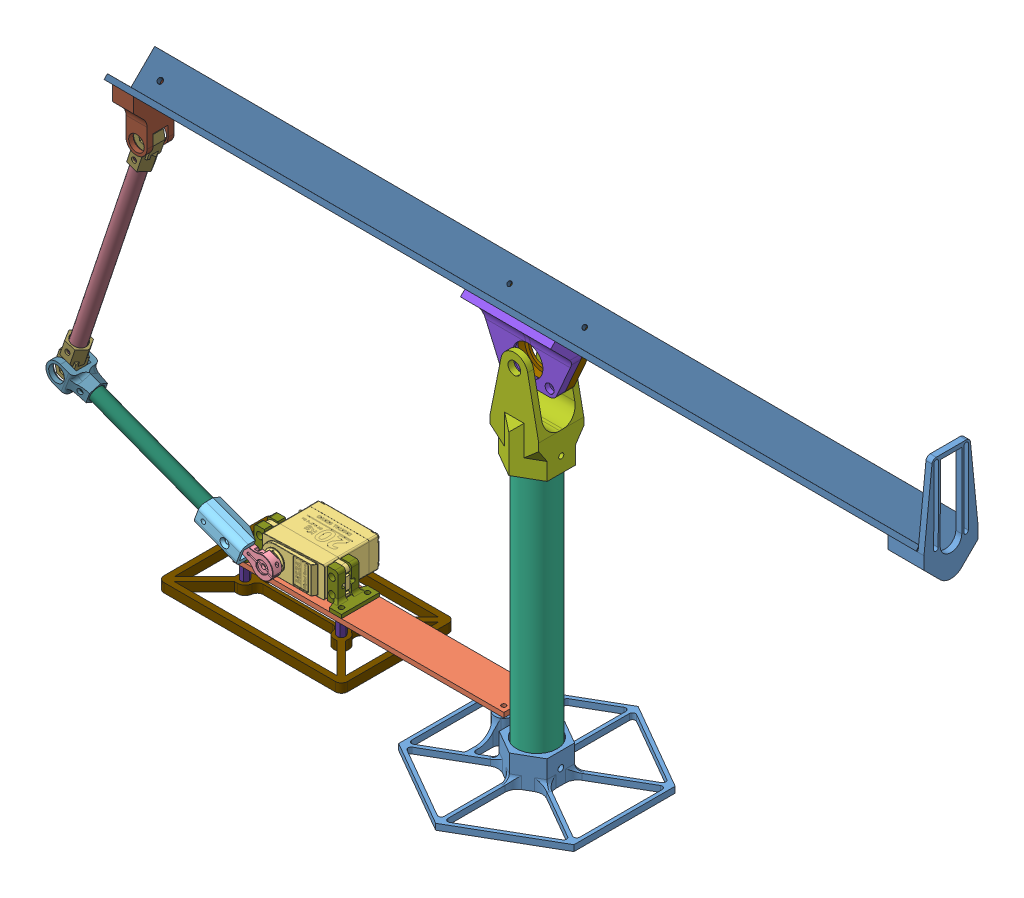
SolidWorks assembly Ensamblaje2, configuration Predeterminado. Lengths in mm.
Overall size (595.06 324.02 134.64).
24 component instances, 19 part files, 50 mates.
Components (placement in the parent):
- Soporte_base-1: Soporte_base [Predeterminado] at (0.7319 45.2828 116.0405) x (0 0 1) z (1 0 0) size (134.64 20.58 116.6)
- platina-1: platina [Predeterminado] at (-115.2681 61.2828 99.3405) size (180 3.17 25.4)
- DS3218MG MS24 Digital Servo 270-1: DS3218MG MS24 Digital Servo 270 [Default] at (-179.2681 74.4678 97.7405) x (0 1 0) z (1 0 0) size (20.1 45.99 55.6)
- Servo Arm for DS3218MG-1: Servo Arm for DS3218MG [Default] at (-179.2681 74.4678 118.9405) x (-0.353521 -0.935426 0) z (-0.935426 0.353521 0) size (14.5 6.15 35.53)
- brazo_servo_acople-1: brazo_servo_acople [Predeterminado] at (-207.7986 85.2502 116.0405) x (-0.353521 -0.935426 0) z (0 0 1) size (14.32 30 14.8)
- Tubo_soporte-1: Tubo_soporte [Predeterminado] at (0.7319 45.2828 116.0405) x (0 0 1) z (-1 0 0) size (25.4 200 25.4)
- Articulacion_eje-1: Articulacion_eje [Predeterminado] at (0.7319 250.2828 116.0405) x (0 0 1) z (-1 0 0) size (37.41 69 32.4)
- Soporte_barra_frontal-1: Soporte_barra_frontal [Predeterminado] at (0.7733 299.2827 116.0405) x (0.999996 -0.002954 0) z (-0.002954 -0.999996 0) size (60 20.96 45.96)
- Soporte_barra_posterior-1: Soporte_barra_posterior [Predeterminado] at (0.7733 299.2827 116.0405) x (-0.999996 0.002954 0) z (-0.002954 -0.999996 0) size (60 20.96 45.96)
- Barra-1: Barra [Predeterminado] at (0.7733 299.2827 116.0405) x (0.999996 -0.002954 0) z (0.002089 0.707104 0.707107) size (540 25.4 25.4)
- acople_rodamiento_barra-1: acople_rodamiento_barra [Predeterminado] at (-256.5755 283.1433 116.0405) x (0 0 -1) z (0.999996 -0.002954 0) size (35.92 41.86 14)
- acople_brazo-1: acople_brazo [Predeterminado] at (-256.5755 283.1433 116.0405) x (0 0 1) z (0.948568 -0.316575 0) size (12.4 24 14.32)
- brazo2-1: brazo2 [Predeterminado] at (-306.9109 132.3211 116.0405) x (0 0 -1) z (0.948568 -0.316575 0) size (9 150 9)
- acople_brazos-1: acople_brazos [Predeterminado] at (-309.7601 123.784 116.0405) x (0 0 -1) z (-0.353521 -0.935426 0) size (18 26 14)
- acople_brazo-2: acople_brazo [Predeterminado] at (-309.7601 123.784 116.0405) x (0 0 -1) z (0.948568 -0.316575 0) size (12.4 24 14.32)
- brazo-100mm-1: brazo-100mm [Predeterminado] at (-301.3413 120.6023 116.0405) x (0 0 1) z (0.353521 0.935426 0) size (9 100 9)
- Soporte_servo-1: Soporte_servo [Predeterminado] at (-143.2681 64.4678 99.3405) size (15 20 25.4)
- Soporte_servo-2: Soporte_servo [Predeterminado] at (-195.2681 64.4678 99.3405) x (-1 0 0) z (0 0 -1) size (15 20 25.4)
- M3_F_TO_F_10MM_STANDOFF.step-1: M3_F_TO_F_10MM_STANDOFF.step [Predeterminado] at (-137.2681 56.2828 108.0405) x (1 0 0) z (0 -1 0) size (5.78 5.78 10)
- M3_F_TO_F_10MM_STANDOFF.step-2: M3_F_TO_F_10MM_STANDOFF.step [Predeterminado] at (-201.2681 56.2828 90.6405) x (1 0 0) z (0 -1 0) size (5.78 5.78 10)
- M3_F_TO_F_10MM_STANDOFF.step-3: M3_F_TO_F_10MM_STANDOFF.step [Predeterminado] at (-137.2681 56.2828 90.6405) x (1 0 0) z (0 -1 0) size (5.78 5.78 10)
- M3_F_TO_F_10MM_STANDOFF.step-4: M3_F_TO_F_10MM_STANDOFF.step [Predeterminado] at (-201.2681 56.2828 108.0405) x (1 0 0) z (0 -1 0) size (5.78 5.78 10)
- base_servo-1: base_servo [Predeterminado] at (-169.2681 45.2828 99.3405) size (122 6 75.4)
- Soporte_sensor-1: Soporte_sensor [Predeterminado] at (272.0721 298.4813 116.0405) x (0 0 -1) z (0.999996 -0.002954 0) size (35.92 75.1 24)
Mates (geometry in assembly coordinates):
- Concéntrica1: concentric aligned: cylinder of Soporte_base-1 through (-29.2681 61.2828 90.6405) axis (0 -1 0) radius 1.8; cylinder of platina-1 through (-29.2681 64.4578 90.6405) axis (0 -1 0) radius 1.5
- Concéntrica2: concentric aligned: cylinder of Soporte_base-1 through (-29.2681 61.2828 108.0405) axis (0 -1 0) radius 1.8; cylinder of platina-1 through (-29.2681 64.4578 108.0405) axis (0 -1 0) radius 1.5
- Coincidente1: coincident anti-aligned: plane of Soporte_base-1 through (0.7319 61.2828 116.0405) normal (0 1 0); plane of platina-1 through (-115.2681 61.2828 99.3405) normal (0 -1 0)
- Concéntrica12: concentric aligned: cylinder of DS3218MG MS24 Digital Servo 270-1 through (-179.2681 74.4678 112.1405) axis (0 0 1) radius 1.25; cylinder of Servo Arm for DS3218MG-1 through (-179.2681 74.4678 112.9405) axis (0 0 1) radius 1.5
- Concéntrica13: concentric aligned: circle of Servo Arm for DS3218MG-1; cylinder of brazo_servo_acople-1 through (-202.186 83.129 97.629) axis (0 0 1) radius 1.5
- Concéntrica14: concentric anti-aligned: circle of Servo Arm for DS3218MG-1; cylinder of brazo_servo_acople-1 through (-198.4443 81.715 124.6405) axis (0 0 -1) radius 1.5
- Concéntrica15: concentric anti-aligned: cylinder of Soporte_base-1 through (-20.5421 55.2828 116.0405) axis (1 0 0) radius 1.9; cylinder of Tubo_soporte-1 through (13.4319 55.2828 116.0405) axis (-1 0 0) radius 1.5
- Concéntrica16: concentric aligned: cylinder of Soporte_base-1 through (0.7319 65.2828 116.0405) axis (0 -1 0) radius 13.5; cylinder of Tubo_soporte-1 through (0.7319 245.2828 116.0405) axis (0 -1 0) radius 12.7
- Concéntrica17: concentric aligned: cylinder of Tubo_soporte-1 through (13.4319 235.2828 116.0405) axis (-1 0 0) radius 1.5; cylinder of Articulacion_eje-1 through (21.7402 235.2828 116.0405) axis (-1 0 0) radius 1.7
- Concéntrica18: concentric anti-aligned: cylinder of Tubo_soporte-1 through (0.7319 245.2828 116.0405) axis (0 -1 0) radius 12.7; cylinder of Articulacion_eje-1 through (0.7319 225.2828 116.0405) axis (0 1 0) radius 13.1
- Coincidente5: coincident anti-aligned: plane of Soporte_barra_frontal-1 through (-29.2266 299.3713 116.0405) normal (0 0 -1); plane of Soporte_barra_posterior-1 through (30.7731 299.1941 116.0405) normal (0 0 1)
- Concéntrica19: concentric anti-aligned: cylinder of Soporte_barra_frontal-1 through (0.7319 285.2828 154.0444) axis (0 0 -1) radius 10; cylinder of Soporte_barra_posterior-1 through (0.7319 285.2828 78.0366) axis (0 0 1) radius 10
- Concéntrica20: concentric anti-aligned: cylinder of Soporte_barra_posterior-1 through (25.7805 301.6891 100.5602) axis (0.002089 0.707104 0.707107) radius 1.75; cylinder of Barra-1 through (25.8166 313.9341 112.8053) axis (-0.002089 -0.707104 -0.707107) radius 1.5
- Concéntrica21: concentric aligned: cylinder of Soporte_barra_frontal-1 through (-24.2048 306.751 126.6065) axis (-0.002089 -0.707104 0.707107) radius 3; cylinder of Barra-1 through (-24.1831 314.0818 119.2757) axis (-0.002089 -0.707104 0.707107) radius 1.5
- Ancho2: width anti-aligned: plane of Soporte_barra_frontal-1 through (-29.3093 271.3715 122.0405) normal (0 0 1); plane of Soporte_barra_posterior-1 through (30.6904 271.1942 110.0405) normal (0 0 -1); plane of Articulacion_eje-1 through (0.7319 250.2828 127.0405) normal (0 0 -1); plane of Articulacion_eje-1 through (0.7319 250.2828 105.0405) normal (0 0 1)
- Concéntrica22: concentric aligned: cylinder of Articulacion_eje-1 through (0.7319 285.2828 101.0405) axis (0 0 1) radius 4.2; cylinder of Soporte_barra_posterior-1 through (0.7319 285.2828 111.6405) axis (0 0 1) radius 12.5
- Ancho3: width anti-aligned: plane of acople_rodamiento_barra-1 through (-256.5755 283.1433 111.0405) normal (0 0 1); plane of acople_rodamiento_barra-1 through (-256.5755 283.1433 121.0405) normal (0 0 -1); plane of acople_brazo-1 through (-256.5755 283.1433 111.4405) normal (0 0 -1); plane of acople_brazo-1 through (-256.5755 283.1433 120.6405) normal (0 0 1)
- Concéntrica23: concentric aligned: cylinder of acople_rodamiento_barra-1 through (-256.5755 283.1433 122.0405) axis (0 0 1) radius 5.2; circle of acople_brazo-1
- Concéntrica24: concentric anti-aligned: cylinder of Barra-1 through (-256.4821 314.768 119.2757) axis (-0.002089 -0.707104 0.707107) radius 1.75; cylinder of acople_rodamiento_barra-1 through (-256.5238 300.6733 133.3705) axis (0.002089 0.707104 -0.707107) radius 1.7
- Concéntrica25: concentric anti-aligned: cylinder of Barra-1 through (-256.4821 314.768 112.8053) axis (-0.002089 -0.707104 -0.707107) radius 1.75; cylinder of acople_rodamiento_barra-1 through (-256.5238 300.6733 98.7105) axis (0.002089 0.707104 0.707107) radius 1.7
- Concéntrica26: concentric anti-aligned: cylinder of acople_brazo-1 through (-261.0076 269.8634 109.8405) axis (0 0 1) radius 1.7; cylinder of brazo2-1 through (-261.0076 269.8634 120.5405) axis (0 0 -1) radius 1.5
- Concéntrica27: concentric anti-aligned: cylinder of acople_brazo-1 through (-262.5905 265.1206 116.0405) axis (0.316575 0.948568 0) radius 5; cylinder of brazo2-1 through (-259.4247 274.6062 116.0405) axis (-0.316575 -0.948568 0) radius 4.5
- Concéntrica28: concentric aligned: cylinder of brazo2-1 through (-305.328 137.0639 120.5405) axis (0 0 -1) radius 1.5; cylinder of acople_brazo-2 through (-305.328 137.0639 122.2405) axis (0 0 -1) radius 1.7
- Concéntrica29: concentric aligned: cylinder of brazo2-1 through (-259.4247 274.6062 116.0405) axis (-0.316575 -0.948568 0) radius 4.5; cylinder of acople_brazo-2 through (-303.7452 141.8068 116.0405) axis (-0.316575 -0.948568 0) radius 5
- Ancho4: width anti-aligned: plane of acople_brazos-1 through (-309.7601 123.784 111.0405) normal (0 0 1); plane of acople_brazos-1 through (-309.7601 123.784 121.0405) normal (0 0 -1); plane of acople_brazo-2 through (-309.7601 123.784 111.4405) normal (0 0 -1); plane of acople_brazo-2 through (-309.7601 123.784 120.6405) normal (0 0 1)
- Concéntrica30: concentric anti-aligned: cylinder of acople_brazos-1 through (-309.7601 123.784 122.0405) axis (0 0 1) radius 5.2; circle of acople_brazo-2
- Concéntrica31: concentric anti-aligned: cylinder of acople_brazos-1 through (-296.6641 118.8347 125.0405) axis (0 0 -1) radius 1.7; cylinder of brazo-100mm-1 through (-296.6641 118.8347 111.5405) axis (0 0 1) radius 1.5
- Concéntrica32: concentric aligned: cylinder of acople_brazos-1 through (-291.987 117.0671 116.0405) axis (-0.935426 0.353521 0) radius 5; cylinder of brazo-100mm-1 through (-207.7986 85.2502 116.0405) axis (-0.935426 0.353521 0) radius 4.5
- Concéntrica33: concentric anti-aligned: cylinder of brazo_servo_acople-1 through (-212.4757 87.0178 124.6405) axis (0 0 -1) radius 1.5; cylinder of brazo-100mm-1 through (-212.4757 87.0178 111.5405) axis (0 0 1) radius 1.5
- Concéntrica34: concentric anti-aligned: cylinder of brazo_servo_acople-1 through (-217.1529 88.7854 116.0405) axis (0.935426 -0.353521 0) radius 5; cylinder of brazo-100mm-1 through (-207.7986 85.2502 116.0405) axis (-0.935426 0.353521 0) radius 4.5
- Coincidente7: coincident anti-aligned: plane of Servo Arm for DS3218MG-1 through (-179.2681 74.4678 114.9405) normal (0 0 -1); plane of brazo_servo_acople-1 through (-207.7986 85.2502 114.9405) normal (0 0 1)
- Concéntrica38: concentric anti-aligned: cylinder of DS3218MG MS24 Digital Servo 270-1 through (-193.2681 79.4678 91.3765) axis (0 0 1) radius 2.25; cylinder of Soporte_servo-2 through (-193.2681 79.4678 112.563) axis (0 0 -1) radius 2.2
- Concéntrica39: concentric aligned: cylinder of DS3218MG MS24 Digital Servo 270-1 through (-145.2681 69.4678 91.3765) axis (0 0 1) radius 2.25; cylinder of Soporte_servo-1 through (-145.2681 69.4678 86.1179) axis (0 0 1) radius 2.2
- Concéntrica40: concentric aligned: cylinder of platina-1 through (-201.2681 64.4578 108.0405) axis (0 -1 0) radius 1.5; cylinder of Soporte_servo-2 through (-201.2681 75.895 108.0405) axis (0 -1 0) radius 1.6
- Concéntrica41: concentric aligned: cylinder of platina-1 through (-137.2681 64.4578 90.6405) axis (0 -1 0) radius 1.5; cylinder of Soporte_servo-1 through (-137.2681 75.895 90.6405) axis (0 -1 0) radius 1.6
- Coincidente8: coincident anti-aligned: plane of platina-1 through (-115.2681 64.4578 99.3405) normal (0 1 0); plane of DS3218MG MS24 Digital Servo 270-1 through (-169.099 64.4578 93.2687) normal (0 -1 0)
- Ancho5: width anti-aligned: plane of DS3218MG MS24 Digital Servo 270-1 through (-152.2681 83.4678 97.7405) normal (0 0 -1); plane of DS3218MG MS24 Digital Servo 270-1 through (-179.2681 74.4678 100.9405) normal (0 0 1); plane of Soporte_servo-2 through (-190.2681 64.4678 97.3405) normal (0 0 1); plane of Soporte_servo-2 through (-190.2681 64.4678 101.3405) normal (0 0 -1)
- Coincidente9: coincident aligned: plane of M3_F_TO_F_10MM_STANDOFF.step-2 through (-201.2681 61.2828 90.6405) normal (0 1 0); plane of M3_F_TO_F_10MM_STANDOFF.step-4 through (-201.2681 61.2828 108.0405) normal (0 1 0)
- Coincidente10: coincident aligned: plane of M3_F_TO_F_10MM_STANDOFF.step-2 through (-201.2681 61.2828 90.6405) normal (0 1 0); plane of M3_F_TO_F_10MM_STANDOFF.step-3 through (-137.2681 61.2828 90.6405) normal (0 1 0)
- Coincidente11: coincident aligned: plane of M3_F_TO_F_10MM_STANDOFF.step-1 through (-137.2681 61.2828 108.0405) normal (0 1 0); plane of M3_F_TO_F_10MM_STANDOFF.step-2 through (-201.2681 61.2828 90.6405) normal (0 1 0)
- Coincidente12: coincident anti-aligned: plane of platina-1 through (-115.2681 61.2828 99.3405) normal (0 -1 0); plane of M3_F_TO_F_10MM_STANDOFF.step-2 through (-201.2681 61.2828 90.6405) normal (0 1 0)
- Concéntrica42: concentric aligned: cylinder of platina-1 through (-201.2681 64.4578 90.6405) axis (0 -1 0) radius 1.5; cylinder of M3_F_TO_F_10MM_STANDOFF.step-2 through (-201.2681 51.2828 90.6405) axis (0 -1 0) radius 1.25
- Concéntrica43: concentric aligned: cylinder of platina-1 through (-137.2681 64.4578 90.6405) axis (0 -1 0) radius 1.5; cylinder of M3_F_TO_F_10MM_STANDOFF.step-3 through (-137.2681 51.2828 90.6405) axis (0 -1 0) radius 1.25
- Concéntrica44: concentric aligned: cylinder of platina-1 through (-137.2681 64.4578 108.0405) axis (0 -1 0) radius 1.5; cylinder of M3_F_TO_F_10MM_STANDOFF.step-1 through (-137.2681 51.2828 108.0405) axis (0 -1 0) radius 1.25
- Concéntrica45: concentric aligned: cylinder of platina-1 through (-201.2681 64.4578 108.0405) axis (0 -1 0) radius 1.5; cylinder of M3_F_TO_F_10MM_STANDOFF.step-4 through (-201.2681 51.2828 108.0405) axis (0 -1 0) radius 1.25
- Concéntrica46: concentric aligned: cylinder of M3_F_TO_F_10MM_STANDOFF.step-2 through (-201.2681 51.2828 90.6405) axis (0 -1 0) radius 1.25; cylinder of base_servo-1 through (-201.2681 51.2828 90.6405) axis (0 -1 0) radius 1.6
- Concéntrica47: concentric aligned: cylinder of M3_F_TO_F_10MM_STANDOFF.step-1 through (-137.2681 51.2828 108.0405) axis (0 -1 0) radius 1.25; cylinder of base_servo-1 through (-137.2681 51.2828 108.0405) axis (0 -1 0) radius 1.6
- Coincidente13: coincident anti-aligned: plane of M3_F_TO_F_10MM_STANDOFF.step-4 through (-201.2681 51.2828 108.0405) normal (0 -1 0); plane of base_servo-1 through (-169.2681 51.2828 99.3405) normal (0 1 0)
- Concéntrica48: concentric anti-aligned: cylinder of Barra-1 through (258.1156 313.2479 112.8053) axis (-0.002089 -0.707104 -0.707107) radius 1.75; cylinder of Soporte_sensor-1 through (258.0755 299.6603 99.2176) axis (0.002089 0.707104 0.707107) radius 1.8
- Concéntrica49: concentric aligned: cylinder of Barra-1 through (258.1156 313.2479 119.2757) axis (-0.002089 -0.707104 0.707107) radius 1.75; cylinder of Soporte_sensor-1 through (258.0945 306.0887 126.4349) axis (-0.002089 -0.707104 0.707107) radius 3.2
